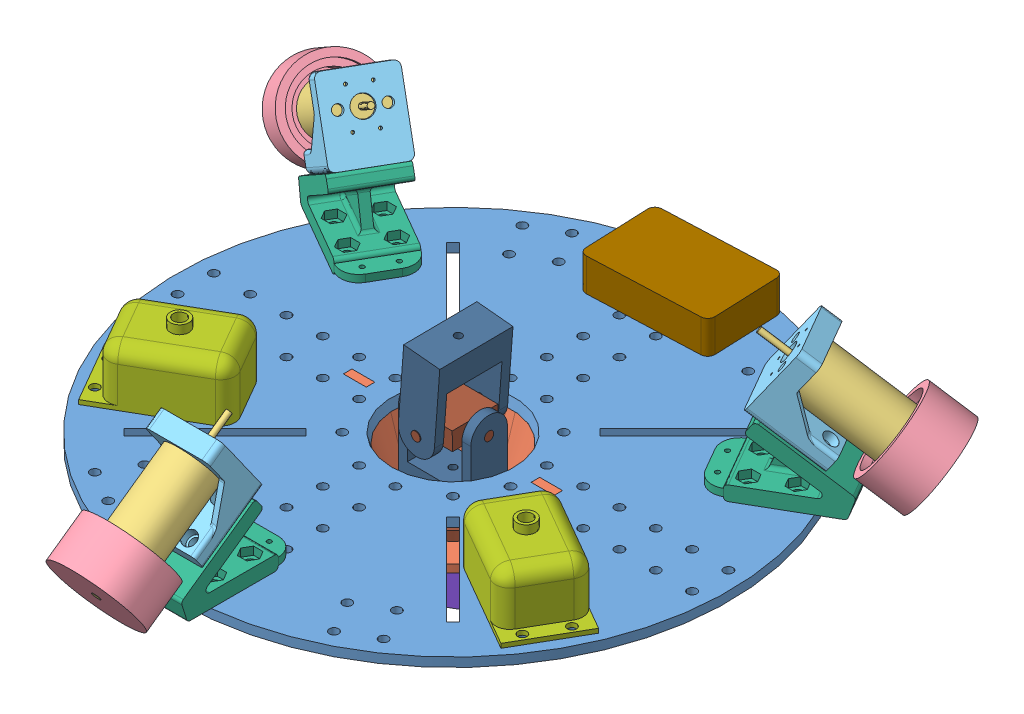
SolidWorks assembly LAT2_0_big, configuration Default. Lengths in mm.
Overall size (515.84 203.83 472.17).
25 component instances, 12 part files, 23 mates.
Components (placement in the parent):
- BodyPlate_bigger-1: BodyPlate_bigger [Default] at (-22.9439 32.8916 5.4719) size (385.3 46.25 385.3)
- PlateSupport_big-1: PlateSupport_big [Default] at (-22.9439 32.8916 5.4719) size (240 46.25 240)
- RWMotor-1: RWMotor [Default] at (64.0516 15.3261 234.257) x (0 0.577288 -0.816541) z (-0.234834 0.793707 0.561144) size (113.8 86 86)
  - motor_withshaft-1: motor_withshaft [Default] at (114.1916 63.2299 66.0433) size (113.8 34.9 34.9)
  - reactionWheel_noshaft-1: reactionWheel_noshaft [Default] at (21.0703 73.5429 66.0433) x (0 -0.760425 0.649425) z (0 0.649425 0.760425) size (61 30.5 61)
  - reactionWheelMount-1: reactionWheelMount [Default] at (52.024 80.7007 36.4157) x (0 -0.972036 -0.234834) z (0 -0.234834 0.972036) size (44.45 50.8 50.8)
- angle35withMarker-1: angle35withMarker [Default] at (-45.1689 32.8916 213.3617) x (0 0 -1) z (1 0 0) size (80.26 49.82 44.45)
- RWMotor-2: RWMotor [Default] at (-264.5754 15.3261 -33.5803) x (0.707145 0.577288 0.40827) z (-0.368548 0.793707 -0.483944) size (113.8 86 86)
  - motor_withshaft-1: motor_withshaft [Default] at (114.1916 63.2299 66.0433) size (113.8 34.9 34.9)
  - reactionWheel_noshaft-1: reactionWheel_noshaft [Default] at (21.0703 73.5429 66.0433) x (0 -0.760425 0.649425) z (0 0.649425 0.760425) size (61 30.5 61)
  - reactionWheelMount-1: reactionWheelMount [Default] at (52.024 80.7007 36.4157) x (0 -0.972036 -0.234834) z (0 -0.234834 0.972036) size (44.45 50.8 50.8)
- RWMotor-3: RWMotor [Default] at (131.692 15.3261 -184.261) x (-0.707145 0.577288 0.40827) z (0.603382 0.793707 -0.0772) size (113.8 86 86)
  - motor_withshaft-1: motor_withshaft [Default] at (114.1916 63.2299 66.0433) size (113.8 34.9 34.9)
  - reactionWheel_noshaft-1: reactionWheel_noshaft [Default] at (21.0703 73.5429 66.0433) x (0 -0.760425 0.649425) z (0 0.649425 0.760425) size (61 30.5 61)
  - reactionWheelMount-1: reactionWheelMount [Default] at (52.024 80.7007 36.4157) x (0 -0.972036 -0.234834) z (0 -0.234834 0.972036) size (44.45 50.8 50.8)
- angle35withMarker-2: angle35withMarker [Default] at (-191.8693 32.8916 -117.7204) x (0.866025 0 0.5) z (-0.5 0 0.866025) size (80.26 49.82 44.45)
- angle35withMarker-3: angle35withMarker [Default] at (168.2064 32.8916 -79.2256) x (-0.866025 0 0.5) z (-0.5 0 -0.866025) size (80.26 49.82 44.45)
- FuelTank-2: FuelTank [Default] at (-131.644 53.3916 97.0974) x (-0.5 0 -0.866025) z (-0.866025 0 0.5) size (50 44 80)
- FuelTank-3: FuelTank [Default] at (110.7561 53.3916 53.7962) x (-0.5 0 0.866025) z (0.866025 0 0.5) size (50 44 80)
- battery-1: battery [Default] at (-61.0502 -35.3584 -33.2003) x (0.866025 0 -0.5) z (0.5 0 0.866025) size (34 22 105)
- boards-1: boards [Default] at (-39.8999 32.8916 -140.8624) x (0.040734 0 0.99917) z (-0.99917 0 0.040734) size (55 23 87)
- hang1-1: hang1 [Default] at (2.4784 29.3615 9.9182) x (-0.006344 0 0.99998) z (-0.99998 0 -0.006344) size (25.45 63.45 50.9)
- hang2-1: hang2 [Default] at (-7.5798 53.5373 50.5775) x (-0.006343 -0.015595 0.999858) z (-0.99998 0 -0.006344) size (51.4 12.7 51.4)
- hang1-2: hang1 [Default] at (-26.0352 58.1005 -20.0215) x (-0.995904 0.090279 -0.00491) z (-0.006343 -0.015595 0.999858) size (25.45 63.45 50.9)
- BatteryMount-1: BatteryMount [Default] at (-15.4439 -45.5184 18.4623) x (0.866025 0 -0.5) z (0.5 0 0.866025) size (117.08 32.16 30)
Mates (geometry in assembly coordinates):
- Coincident1: coincident anti-aligned: plane of BodyPlate_bigger-1 through (34.7059 26.5416 2.4719) normal (1 0 0); plane of PlateSupport_big-1 through (34.7059 26.5416 2.4719) normal (-1 0 0)
- Coincident2: coincident anti-aligned: plane of BodyPlate_bigger-1 through (50.7059 26.5416 2.4719) normal (-1 0 0); plane of PlateSupport_big-1 through (50.7059 26.5416 2.4719) normal (1 0 0)
- Coincident3: coincident aligned: line of BodyPlate_bigger-1 through (50.7059 32.8916 8.4719) axis (-1 0 0); line of PlateSupport_big-1 through (50.7059 32.8916 8.4719) axis (-1 0 0)
- Concentric1: concentric anti-aligned: circle of BodyPlate_bigger-1; circle of angle35withMarker-1
- Concentric2: concentric anti-aligned: circle of BodyPlate_bigger-1; circle of angle35withMarker-1
- Coincident4: coincident anti-aligned: circle of BodyPlate_bigger-1; plane of angle35withMarker-1 through (-0.7189 32.8916 213.3617) normal (0 -1 0)
- Coincident6: coincident anti-aligned: circle of RWMotor-1/reactionWheelMount-1; circle of angle35withMarker-1
- Coincident7: coincident anti-aligned: circle of RWMotor-1/reactionWheelMount-1; circle of angle35withMarker-1
- Coincident12: coincident anti-aligned: plane of BodyPlate_bigger-1 through (19.7059 32.8916 5.4719) normal (0 1 0); plane of FuelTank-2 through (-131.644 32.8916 97.0974) normal (0 -1 0)
- Coincident13: coincident anti-aligned: circle of BodyPlate_bigger-1; circle of FuelTank-2
- Coincident15: coincident anti-aligned: circle of BodyPlate_bigger-1; circle of FuelTank-2
- Coincident16: coincident anti-aligned: plane of BodyPlate_bigger-1 through (19.7059 32.8916 5.4719) normal (0 1 0); plane of boards-1 through (-62.0901 32.8916 -174.9267) normal (0 -1 0)
- Coincident18: coincident anti-aligned: plane of BodyPlate_bigger-1 through (169.7059 26.5416 5.4719) normal (0 -1 0); plane of PlateSupport_big-1 through (-22.9439 26.5416 5.4719) normal (0 1 0)
- Concentric3: concentric anti-aligned: circle of PlateSupport_big-1; circle of hang1-1
- Coincident19: coincident anti-aligned: plane of PlateSupport_big-1 through (-22.9439 -7.3584 5.4719) normal (0 1 0); plane of hang1-1 through (-48.3127 -7.3584 -7.4143) normal (0 -1 0)
- Coincident20: coincident aligned: circle of hang1-1; circle of hang2-1
- Coincident21: coincident anti-aligned: plane of hang2-1 through (-23.0309 43.7674 -20.226) normal (0.006343 0.015595 -0.999858); circle of hang1-2
- Concentric4: concentric aligned: cylinder of hang2-1 through (-23.357 42.9658 31.1667) axis (0.006343 0.015595 -0.999858) radius 3.175; cylinder of hang1-2 through (-23.3538 42.9736 30.6667) axis (0.006343 0.015595 -0.999858) radius 3.175
- Coincident22: coincident anti-aligned: plane of battery-1 through (-6.8182 -35.3584 56.7324) normal (0 -1 0); plane of BatteryMount-1 through (-14.5653 -35.3584 -16.686) normal (0 1 0)
- Parallel1: parallel anti-aligned: line of battery-1 through (-8.5502 -33.3584 57.7324) axis (-0.5 0 -0.866025); line of BatteryMount-1 through (-46.3226 -35.3584 1.6491) axis (0.5 0 0.866025)
- Coincident24: coincident anti-aligned: circle of PlateSupport_big-1; circle of BatteryMount-1
- Coincident25: coincident anti-aligned: circle of PlateSupport_big-1; cylinder of BatteryMount-1 through (16.8932 -45.5194 -17.5281) axis (0 1 0) radius 3.2
- Coincident26: coincident anti-aligned: line of battery-1 through (19.1626 -35.3584 41.7324) axis (-0.5 0 -0.866025); line of BatteryMount-1 through (-14.5653 -35.3584 -16.686) axis (0.5 0 0.866025)
